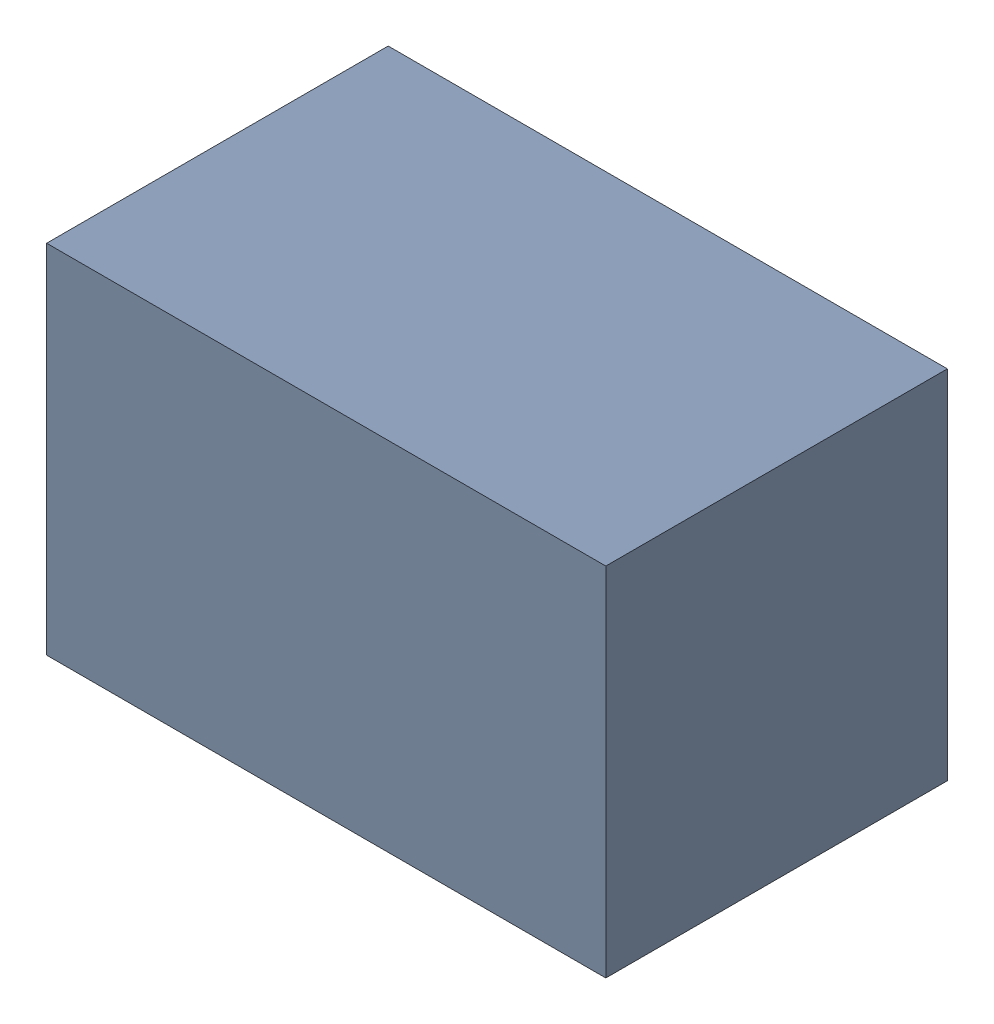
SolidWorks assembly C42, configuration Default. Lengths in mm.
Overall size (2.21 1.41 1.35).
3 component instances, 2 part files, 0 mates.
Components (placement in the parent):
- 1088885792-1: 1088885792 [Default] at (9.225 17.1 -2.994) size (2.21 1.41 1.35)
  - Extruded-46-1: Extruded-46 [Default] at origin size (2.21 1.41 1.35)
- C0805_2012D-1: C0805_2012D [Default] at (8.225 17.7251 -1.644) x (1 0 0) z (0 1 0) size (2 1.25 1.25)
